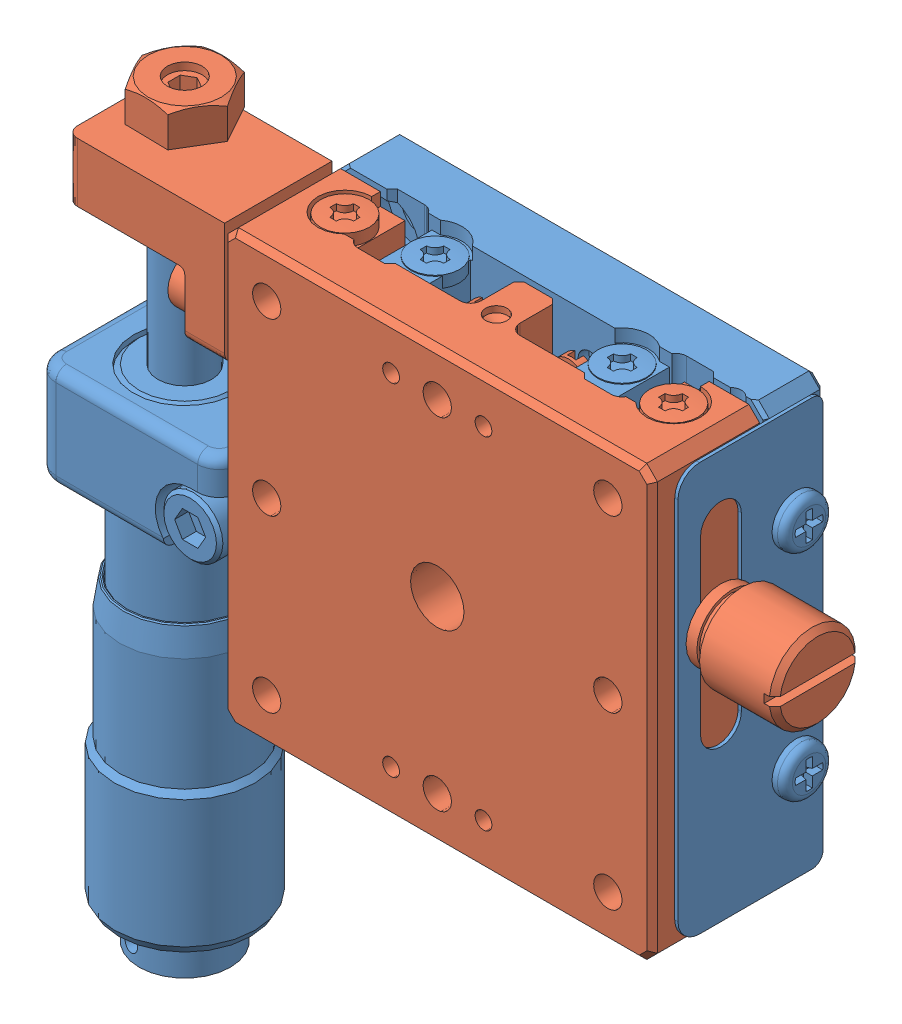
SolidWorks assembly 122-0070, configuration Default. Lengths in mm.
Overall size (67.4 70.2 16).
2 component instances, 2 part files, 0 mates.
Components (placement in the parent):
- TSD-401SUU-C1B-S07-1: TSD-401SUU-C1B-S07 [Default] at origin size (59.6 67 15.55)
- TSD-401SUU-C1B-S08-1: TSD-401SUU-C1B-S08 [Default] at (0 0 16) size (64.1 43.23 10.9)
